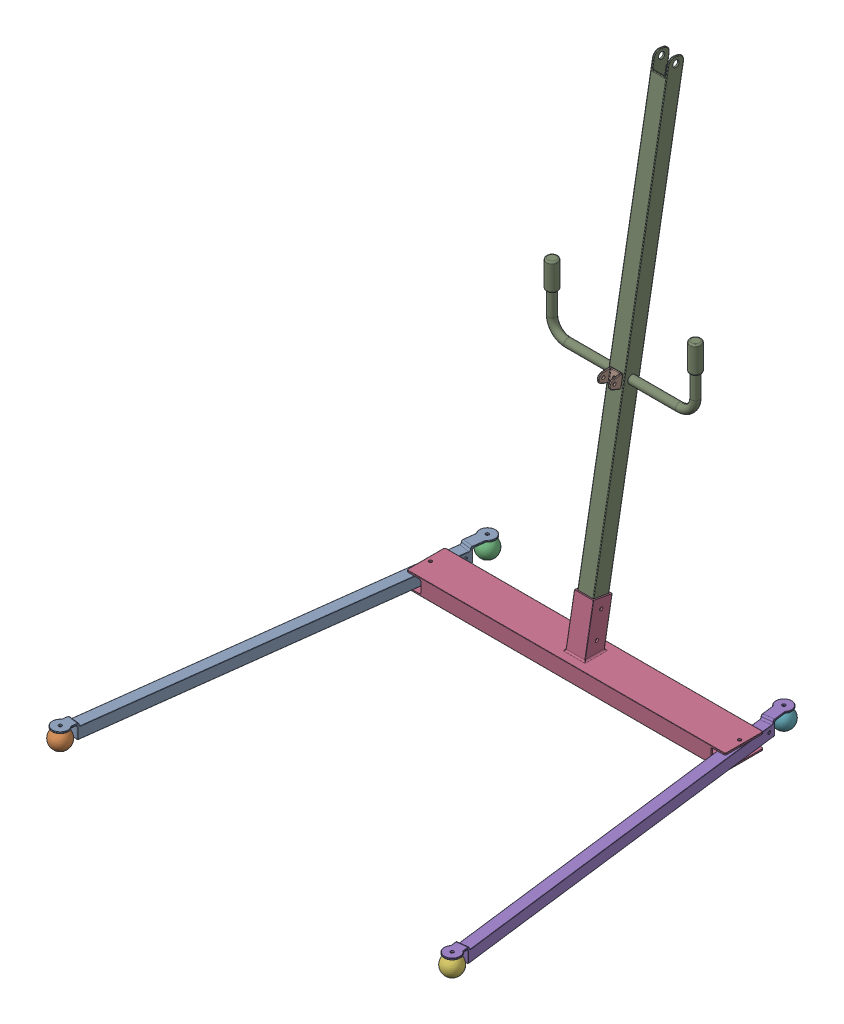
SolidWorks assembly 底座, configuration 默认. Lengths in mm.
Overall size (1291.32 1565.52 1351.07).
9 component instances, 5 part files, 19 mates.
Components (placement in the parent):
- 脚纵梁-1: 脚纵梁 [默认] at (-472.5 -22.5 -159.2157) x (0.992157 0 0.125) z (-0.125 0 0.992157) size (50 45 1250)
- 脚轮球-1: 脚轮球 [默认] at (-615 -29.5804 971.843) x (-0.999751 0 -0.022319) z (0.022319 0 -0.999751) size (60 59.58 60)
- 脚轮球-2: 脚轮球 [默认] at (-465 -29.5804 -218.7451) size (60 59.58 60)
- 脚横梁-1: 脚横梁 [默认] at (-500 -25 -60) x (0 0 -1) z (1 0 0) size (120 202.93 1000)
- 脚纵梁-2: 脚纵梁 [默认] at (472.5 -22.5 -159.2157) x (0.992157 0 -0.125) z (0.125 0 0.992157) size (50 45 1250)
- 脚轮球-3: 脚轮球 [默认] at (615 -29.5804 971.843) x (-0.999751 0 -0.022319) z (0.022319 0 -0.999751) size (60 59.58 60)
- 脚轮球-4: 脚轮球 [默认] at (465 -29.5804 -218.7451) size (60 59.58 60)
- U型接头-1: U型接头 [默认] at (0 693.7066 -156.9335) x (1 0 0) z (0 0.173648 0.984808) size (40 40 40)
- 支撑柱-1: 支撑柱 [默认] at (0 19.6962 -63.473) x (1 0 0) z (0 0.984808 -0.173648) size (485 77.04 1500)
Mates (geometry in assembly coordinates):
- 同心1: concentric aligned: cylinder of 脚纵梁-1 through (-465 0 -218.7451) axis (0 1 0) radius 5; cylinder of 脚轮球-2 through (-465 0.4196 -218.7451) axis (0 1 0) radius 5
- 重合1: coincident anti-aligned: plane of 脚纵梁-1 through (-472.5 0 -159.2157) normal (0 -1 0); circle of 脚轮球-2
- 重合2: coincident aligned: circle of 脚纵梁-1; circle of 脚轮球-1
- 同心2: concentric aligned: cylinder of 脚纵梁-1 through (-485 -40 -60) axis (0 1 0) radius 5; cylinder of 脚横梁-1 through (-485 -50 -60) axis (0 1 0) radius 5
- 重合4: coincident anti-aligned: plane of 脚纵梁-1 through (-627.3627 -5 929.9692) normal (0 1 0); plane of 脚横梁-1 through (500 -5 -60) normal (0 -1 0)
- 同心3: concentric aligned: cylinder of 脚横梁-1 through (485 -50 -60) axis (0 1 0) radius 5; cylinder of 脚纵梁-2 through (485 -40 -60) axis (0 1 0) radius 5
- 重合5: coincident aligned: plane of 脚纵梁-1 through (-627.3627 -5 929.9692) normal (0 1 0); plane of 脚纵梁-2 through (592.6373 -5 934.3442) normal (0 1 0)
- 重合6: coincident aligned: plane of 脚横梁-1 through (500 0 -120) normal (0 1 0)
- 重合7: coincident aligned: plane of 脚横梁-1 through (500 0 0) normal (0 0 1)
- 对称3: symmetric aligned: plane of 脚横梁-1 through (-30 152.9306 -56.503) normal (-1 0 0); plane of 脚横梁-1 through (30 152.9306 -56.503) normal (1 0 0)
- 距离1: distance = 930 mm: cylinder of 脚纵梁-2 through (465 0 -218.7451) axis (0 1 0) radius 5; cylinder of 脚纵梁-1 through (-465 0 -218.7451) axis (0 1 0) radius 5
- 对称4: symmetric aligned: cylinder of 脚纵梁-1 through (-465 0 -218.7451) axis (0 1 0) radius 5; cylinder of 脚纵梁-2 through (465 0 -218.7451) axis (0 1 0) radius 5
- 重合8: coincident aligned: circle of 脚纵梁-2; circle of 脚轮球-4
- 重合9: coincident aligned: circle of 脚纵梁-2; circle of 脚轮球-3
- 同心4: concentric aligned: cylinder of 脚横梁-1 through (-500 118.1769 -80.8378) axis (1 0 0) radius 5; cylinder of 支撑柱-1 through (-25 118.1769 -80.8378) axis (1 0 0) radius 5
- 同心5: concentric aligned: cylinder of 脚横梁-1 through (-500 39.3923 -66.9459) axis (1 0 0) radius 5; cylinder of 支撑柱-1 through (-25 39.3923 -66.9459) axis (1 0 0) radius 5
- 对称6: symmetric aligned: plane of 支撑柱-1 through (-25 1492.5666 -348.5654) normal (-1 0 0); plane of 支撑柱-1 through (25 1492.5666 -348.5654) normal (1 0 0)
- 重合10: coincident: circle of U型接头-1; circle of 支撑柱-1
- 平行1: parallel aligned: plane of U型接头-1 through (-20 714.271 -155.4825) normal (-1 0 0); plane of 支撑柱-1 through (-25 1492.5666 -348.5654) normal (-1 0 0)
